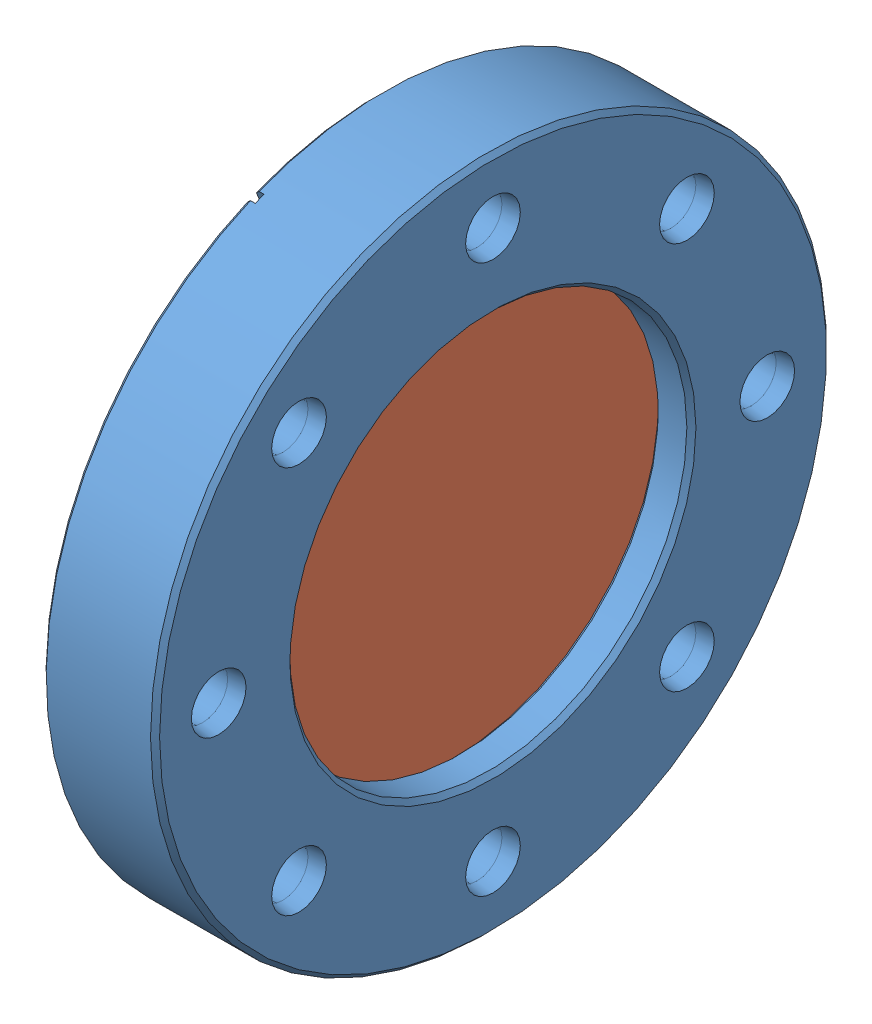
SolidWorks assembly 100018, configuration Default. Lengths in mm.
Overall size (19.06 113.54 113.54).
2 component instances, 2 part files, 2 mates.
Components (placement in the parent):
- 915004-1: 915004 [Default] at (31.8846 54.0944 91.1674) size (19.06 113.54 113.54)
- 910018-1: 910018 [Default] at (32.545 54.0944 91.1674) x (1 0 0) z (0 -0.280857 0.95975) size (11.99 82.32 82.32)
Mates (geometry in assembly coordinates):
- Concentric1: concentric: cylinder of 915004-1 through (31.8846 54.0944 91.1674) axis (-1 0 0) radius 56.769; cylinder of 910018-1 through (44.5846 54.0944 91.1674) axis (1 0 0) radius 41.1607
- Coincident1: coincident anti-aligned: plane of 915004-1 through (44.5846 95.3694 91.1674) normal (-1 0 0); plane of 910018-1 through (44.5846 93.5984 102.7276) normal (1 0 0)
